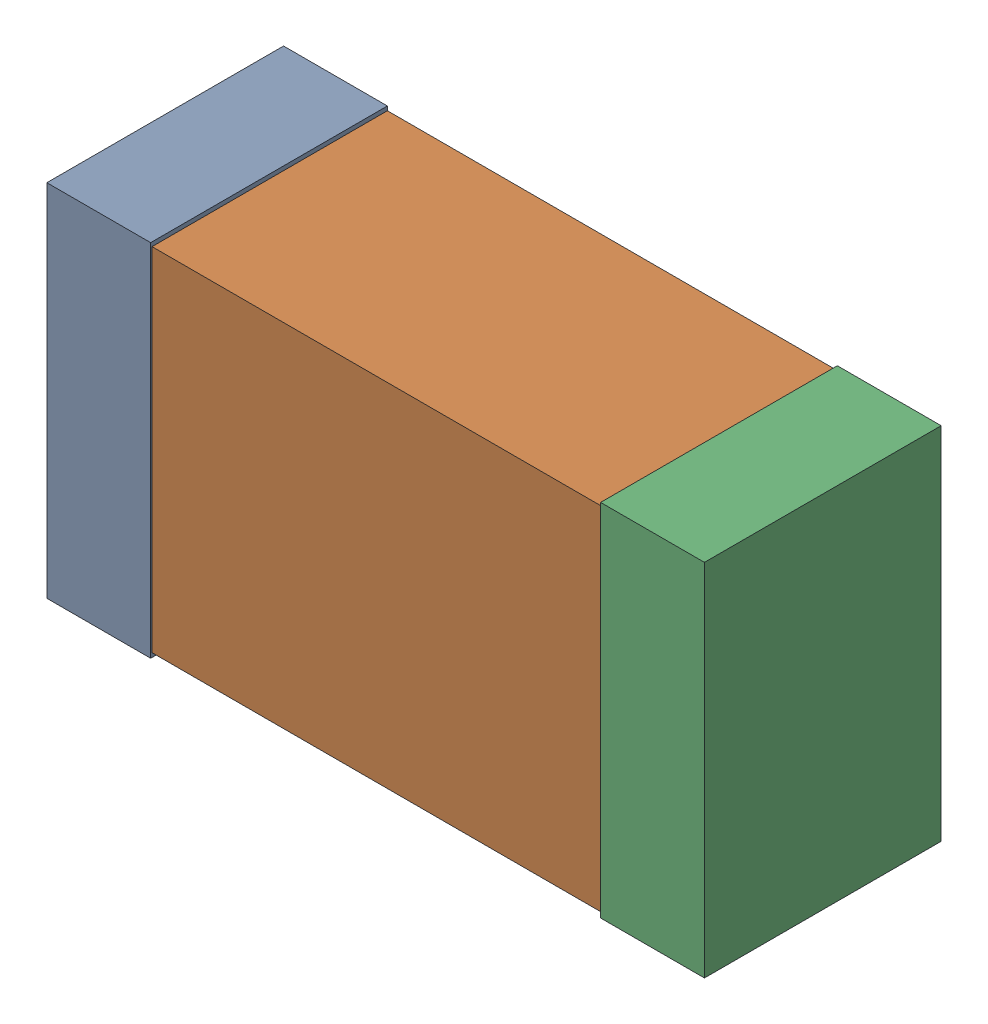
SolidWorks assembly R3_Motor_6Kanaloa_v2.0.0_Motor, configuration Default. Lengths in mm.
Overall size (2.38 1.3 0.85).
6 component instances, 2 part files, 0 mates.
Components (placement in the parent):
- 352877648-1: 352877648 [Default] at (41.614 147.574 0) size (0.38 1.3 0.85)
  - Extruded_14-1: Extruded_14 [Default] at origin size (0.38 1.3 0.85)
- 352877392-1: 352877392 [Default] at (42.614 147.574 0) size (2.2 1.27 0.85)
  - Extruded_15-1: Extruded_15 [Default] at origin size (2.2 1.27 0.85)
- 352877648-2: 352877648 [Default] at (43.614 147.574 0) size (0.38 1.3 0.85)
  - Extruded_14-1: Extruded_14 [Default] at origin size (0.38 1.3 0.85)
